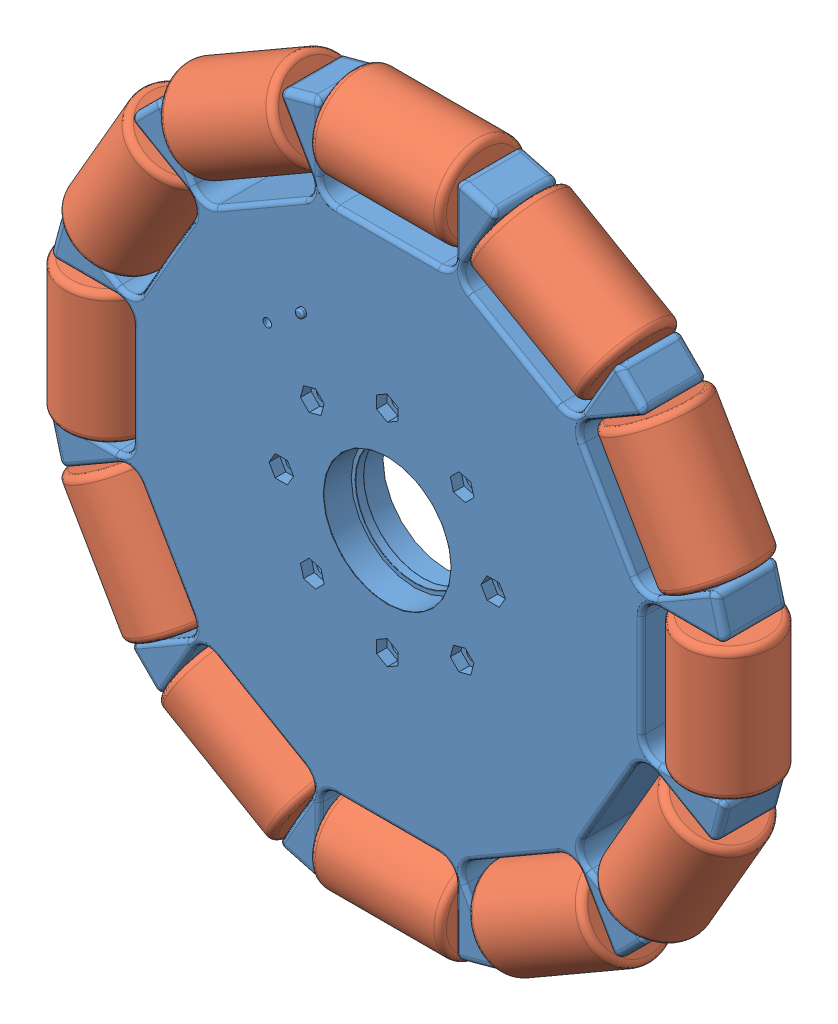
SolidWorks assembly single wheel subassembly 1, configuration Default. Lengths in mm.
13 component instances, 2 part files, 26 mates.
Components (placement in the parent):
- part 1-1: part 1 [Default] at (85.1747 68.7921 110.1764) size (159.09 159.09 16.01)
- roller 2-1: roller 2 [Default] at (100.6747 141.7921 117.6764) x (0 0.48874 -0.87243) z (-1 0 0) size (21 21 31)
- roller 2-2: roller 2 [Default] at (108.2513 -2.1778 117.6764) x (-0.357939 0.619969 0.698225) z (0.866025 0.5 0) size (21 21 31)
- roller 2-3: roller 2 [Default] at (12.1747 84.2921 117.6764) x (0.995031 0 0.099566) z (0 -1 0) size (21 21 31)
- roller 2-4: roller 2 [Default] at (69.6747 -4.2079 117.6764) x (0 0.140994 0.99001) z (1 0 0) size (21 21 31)
- roller 2-5: roller 2 [Default] at (135.0981 124.262 117.6764) x (0.370111 0.641051 -0.672363) z (-0.866025 0.5 0) size (21 21 31)
- roller 2-6: roller 2 [Default] at (14.2048 45.7155 117.6764) x (-0.500231 -0.288808 0.816308) z (0.5 -0.866025 0) size (21 21 31)
- roller 2-7: roller 2 [Default] at (35.2513 13.3222 117.6764) x (0.499957 0.865951 -0.01308) z (0.866025 -0.5 0) size (21 21 31)
- roller 2-8: roller 2 [Default] at (29.7048 118.7155 117.6764) x (0.687396 -0.396868 0.608262) z (-0.5 -0.866025 0) size (21 21 31)
- roller 2-9: roller 2 [Default] at (62.0981 139.762 117.6764) x (0.499652 -0.865423 0.037296) z (-0.866025 -0.5 0) size (21 21 31)
- roller 2-10: roller 2 [Default] at (156.1445 91.8687 117.6764) x (-0.862592 -0.498018 -0.088954) z (-0.5 0.866025 0) size (21 21 31)
- roller 2-11: roller 2 [Default] at (158.1747 53.2921 117.6764) x (-0.046641 0 -0.998912) z (0 1 0) size (21 21 31)
- roller 2-12: roller 2 [Default] at (140.6445 18.8687 117.6764) x (-0.371651 0.214573 -0.903235) z (0.5 0.866025 0) size (21 21 31)
Mates (geometry in assembly coordinates):
- Concentric1: concentric: cylinder of part 1-1 through (30.6663 120.3809 117.6764) axis (-0.5 -0.866025 0) radius 1; cylinder of roller 2-8 through (12.2048 88.4046 117.6764) axis (0.5 0.866025 0) radius 1.025
- Concentric2: concentric: cylinder of part 1-1 through (63.7635 140.7235 117.6764) axis (-0.866025 -0.5 0) radius 1; cylinder of roller 2-9 through (31.7872 122.262 117.6764) axis (0.866025 0.5 0) radius 1.025
- Concentric3: concentric: cylinder of part 1-1 through (102.5977 141.7921 117.6764) axis (-1 0 0) radius 1; cylinder of roller 2-1 through (65.6747 141.7921 117.6764) axis (1 0 0) radius 1.025
- Concentric4: concentric: cylinder of part 1-1 through (136.7635 123.3004 117.6764) axis (-0.866025 0.5 0) radius 1; cylinder of roller 2-5 through (104.7872 141.762 117.6764) axis (0.866025 -0.5 0) radius 1.025
- Concentric5: concentric: cylinder of part 1-1 through (12.1747 86.2152 117.6764) axis (0 -1 0) radius 1; cylinder of roller 2-3 through (12.1747 49.2921 117.6764) axis (0 1 0) radius 1.025
- Concentric6: concentric: cylinder of part 1-1 through (13.2433 47.3809 117.6764) axis (0.5 -0.866025 0) radius 1; cylinder of roller 2-6 through (31.7048 15.4046 117.6764) axis (-0.5 0.866025 0) radius 1.025
- Concentric7: concentric: cylinder of part 1-1 through (33.5859 14.2838 117.6764) axis (0.866025 -0.5 0) radius 1; cylinder of roller 2-7 through (139.9292 -47.1136 117.6764) axis (-0.866025 0.5 0) radius 1.025
- Concentric8: concentric: cylinder of part 1-1 through (67.7516 -4.2079 117.6764) axis (1 0 0) radius 1; cylinder of roller 2-4 through (104.6747 -4.2079 117.6764) axis (-1 0 0) radius 1.025
- Concentric9: concentric: cylinder of part 1-1 through (106.5859 -3.1393 117.6764) axis (0.866025 0.5 0) radius 1; cylinder of roller 2-2 through (138.5622 15.3222 117.6764) axis (-0.866025 -0.5 0) radius 1.025
- Concentric10: concentric: cylinder of part 1-1 through (157.106 90.2033 117.6764) axis (-0.5 0.866025 0) radius 1; cylinder of roller 2-10 through (138.6445 122.1796 117.6764) axis (0.5 -0.866025 0) radius 1.025
- Concentric11: concentric: cylinder of part 1-1 through (158.1747 51.3691 117.6764) axis (0 1 0) radius 1; cylinder of roller 2-11 through (158.1747 88.2921 117.6764) axis (0 -1 0) radius 1.025
- Concentric12: concentric: cylinder of part 1-1 through (139.683 17.2033 117.6764) axis (0.5 0.866025 0) radius 1; cylinder of roller 2-12 through (158.1445 49.1796 117.6764) axis (-0.5 -0.866025 0) radius 1.025
- Width1: width: plane of roller 2-9 through (35.2513 124.262 117.6764) normal (-0.866025 -0.5 0); plane of roller 2-9 through (62.0981 139.762 117.6764) normal (0.866025 0.5 0); plane of part 1-1 through (39.2516 116.1793 125.1764) normal (0.866025 0.5 0); plane of part 1-1 through (67.0977 132.2562 125.1764) normal (-0.866025 -0.5 0)
- Width2: width: plane of roller 2-1 through (69.6747 141.7921 117.6764) normal (-1 0 0); plane of roller 2-1 through (100.6747 141.7921 117.6764) normal (1 0 0); plane of part 1-1 through (69.0977 132.7921 125.1764) normal (1 0 0); plane of part 1-1 through (101.2516 132.7921 125.1764) normal (-1 0 0)
- Width3: width: plane of roller 2-5 through (108.2513 139.762 117.6764) normal (-0.866025 0.5 0); plane of roller 2-5 through (135.0981 124.262 117.6764) normal (0.866025 -0.5 0); plane of part 1-1 through (103.2516 132.2562 125.1764) normal (0.866025 -0.5 0); plane of part 1-1 through (131.0977 116.1793 125.1764) normal (-0.866025 0.5 0)
- Width4: width: plane of roller 2-10 through (140.6445 118.7155 117.6764) normal (-0.5 0.866025 0); plane of roller 2-10 through (156.1445 91.8687 117.6764) normal (0.5 -0.866025 0); plane of part 1-1 through (132.5618 114.7152 125.1764) normal (0.5 -0.866025 0); plane of part 1-1 through (148.6388 86.8691 125.1764) normal (-0.5 0.866025 0)
- Width5: width: plane of roller 2-11 through (158.1747 84.2921 117.6764) normal (0 1 0); plane of roller 2-11 through (158.1747 53.2921 117.6764) normal (0 -1 0); plane of part 1-1 through (149.1747 84.8691 125.1764) normal (0 -1 0); plane of part 1-1 through (149.1747 52.7152 125.1764) normal (0 1 0)
- Width6: width: plane of roller 2-12 through (156.1445 45.7155 117.6764) normal (0.5 0.866025 0); plane of roller 2-12 through (140.6445 18.8687 117.6764) normal (-0.5 -0.866025 0); plane of part 1-1 through (148.6388 50.7152 125.1764) normal (-0.5 -0.866025 0); plane of part 1-1 through (132.5618 22.8691 125.1764) normal (0.5 0.866025 0)
- Width7: width: plane of roller 2-2 through (135.0981 13.3222 117.6764) normal (0.866025 0.5 0); plane of roller 2-2 through (108.2513 -2.1778 117.6764) normal (-0.866025 -0.5 0); plane of part 1-1 through (131.0977 21.405 125.1764) normal (-0.866025 -0.5 0); plane of part 1-1 through (103.2516 5.328 125.1764) normal (0.866025 0.5 0)
- Width8: width: plane of roller 2-4 through (100.6747 -4.2079 117.6764) normal (1 0 0); plane of roller 2-4 through (69.6747 -4.2079 117.6764) normal (-1 0 0); plane of part 1-1 through (101.2516 4.7921 125.1764) normal (-1 0 0); plane of part 1-1 through (69.0977 4.7921 125.1764) normal (1 0 0)
- Width9: width: plane of roller 2-6 through (29.7048 18.8687 117.6764) normal (0.5 -0.866025 0); plane of roller 2-6 through (14.2048 45.7155 117.6764) normal (-0.5 0.866025 0); plane of part 1-1 through (37.7875 22.8691 125.1764) normal (-0.5 0.866025 0); plane of part 1-1 through (21.7106 50.7152 125.1764) normal (0.5 -0.866025 0)
- Width10: width: plane of roller 2-3 through (12.1747 53.2921 117.6764) normal (0 -1 0); plane of roller 2-3 through (12.1747 84.2921 117.6764) normal (0 1 0); plane of part 1-1 through (21.1747 52.7152 125.1764) normal (0 1 0); plane of part 1-1 through (21.1747 84.8691 125.1764) normal (0 -1 0)
- Width11: width: plane of roller 2-8 through (14.2048 91.8687 117.6764) normal (-0.5 -0.866025 0); plane of roller 2-8 through (29.7048 118.7155 117.6764) normal (0.5 0.866025 0); plane of part 1-1 through (21.7106 86.8691 125.1764) normal (0.5 0.866025 0); plane of part 1-1 through (37.7875 114.7152 125.1764) normal (-0.5 -0.866025 0)
- Width12: width: plane of roller 2-9 through (35.2513 124.262 117.6764) normal (-0.866025 -0.5 0); plane of roller 2-9 through (62.0981 139.762 117.6764) normal (0.866025 0.5 0); plane of part 1-1 through (39.2516 116.1793 125.1764) normal (0.866025 0.5 0); plane of part 1-1 through (67.0977 132.2562 125.1764) normal (-0.866025 -0.5 0)
- Width13: width: plane of roller 2-1 through (69.6747 141.7921 117.6764) normal (-1 0 0); plane of roller 2-1 through (100.6747 141.7921 117.6764) normal (1 0 0); plane of part 1-1 through (69.0977 132.7921 125.1764) normal (1 0 0); plane of part 1-1 through (101.2516 132.7921 125.1764) normal (-1 0 0)
- Width14: width: plane of roller 2-7 through (35.2513 13.3222 117.6764) normal (-0.866025 0.5 0); plane of roller 2-7 through (62.0981 -2.1778 117.6764) normal (0.866025 -0.5 0); plane of part 1-1 through (67.0977 5.328 125.1764) normal (-0.866025 0.5 0); plane of part 1-1 through (39.2516 21.405 125.1764) normal (0.866025 -0.5 0)
